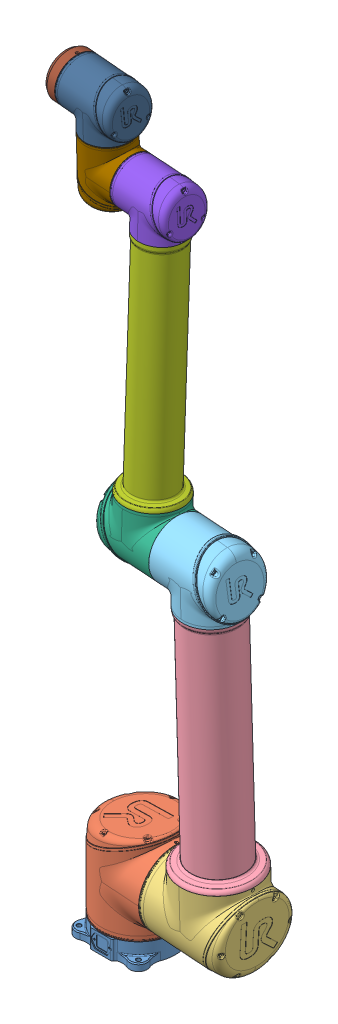
SolidWorks assembly UR10_movable, configuration Default. Lengths in mm.
Overall size (623.67 1479.02 760.18).
13 component instances, 11 part files, 13 mates.
Components (placement in the parent):
- Base-1: Base [Default] at origin size (150 38 151)
- Motor1-1: Motor1 [Default] x (-0.065799 0 0.997833) z (-0.997833 0 -0.065799) size (163.23 199.46 221.51)
- Assem3^UR10_movable-1: Assem3^UR10_movable [Default] at (0.9951 0.8966 -15.0908) x (-0.687172 -0.090957 0.720778) z (-0.726453 0.075412 -0.683066) size (271.39 766.3 275.37) (virtual)
  - Motor2-1: Motor2 [Default] at (8.9202 0.5256 -7.3957) x (0.766663 0.090526 -0.635636) z (0.638256 0 0.769824) size (162.4 221.51 199.46)
  - Link1-1: Link1 [Default] at (-262.9345 -6.1398 -216.9419) x (-0.416864 -0.081693 0.90529) z (-0.906293 -0.039003 -0.420846) size (150 460.6 150)
  - Motor3-1: Motor3 [Default] at (8.4032 1.2693 -6.9671) x (0.766663 0.090526 -0.635636) z (0.638256 0 0.769824) size (122.2 127.99 142.04)
- Assem4^UR10_movable-1: Assem4^UR10_movable [Default] at (18.2939 61.5208 -277.4221) x (-0.681689 -0.358791 0.637628) z (-0.730999 0.297471 -0.614127) size (429.3 645.83 371.98) (virtual)
  - Motor4-1: Motor4 [Default] at (239.8604 95.0312 -198.8668) x (0.668649 0.495561 -0.554373) z (0.638256 0 0.769824) size (122.2 127.38 132.89)
  - Link2-1: Link2 [Default] at (196.8587 74.4286 -194.1564) x (0.88877 0.250612 0.383773) z (-0.254068 -0.42752 0.867569) size (116 451.3 116)
  - Motor5-1: Motor5 [Default] at (178.3443 95.0312 -273.0635) x (-0.668649 -0.495561 0.554373) z (-0.638256 0 -0.769824) size (98 194.56 134.84)
- Motor6-1: Motor6 [Default] at (99.1486 0.3458 -38.7895) x (0.065764 0.03279 -0.997296) z (0.997833 0 0.065799) size (98 134.84 194.56)
- Motor7-1: Motor7 [Default] at (98.9282 0.2491 -35.8503) x (0.083707 0.032784 -0.995951) z (0.996488 -0.00059 0.083733) size (98 194.56 134.84)
- Bracket-1: Bracket [Default] at (96.299 2855.4735 15.5573) x (-0.083735 -0.003243 0.996483) z (0.996488 -0.00059 0.083733) size (90 90.13 30.68)
Mates (geometry in assembly coordinates):
- Concentric1: concentric aligned: cylinder of Base-1 through (0 0 0) axis (0 1 0) radius 75; cylinder of Motor1-1 through (0 210.0029 0) axis (0 1 0) radius 75.01
- Coincident1: coincident anti-aligned: plane of Base-1 through (-53.033 38 -53.033) normal (0 1 0); plane of Motor1-1 through (74.6379 38 4.9218) normal (0 -1 0)
- Coincident9: coincident anti-aligned: plane of Motor6-1 through (-112.0184 1373.607 -7.5637) normal (-0.002158 0.999462 0.032718); plane of Motor7-1 through (-71.0345 1372.1645 39.2036) normal (0.002158 -0.999462 -0.032718)
- Concentric9: concentric aligned: circle of Motor6-1; circle of Motor7-1
- Concentric10: concentric anti-aligned: cylinder of Motor7-1 through (-67.4679 1427.578 -2.8514) axis (-0.996488 0.00059 -0.083733) radius 45; cylinder of Bracket-1 through (-159.3441 1427.6324 -10.5716) axis (0.996488 -0.00059 0.083733) radius 45
- Coincident10: coincident anti-aligned: plane of Motor7-1 through (-129.0478 1472.3543 -6.5532) normal (-0.996488 0.00059 -0.083733); plane of Bracket-1 through (-125.1831 1427.7603 -52.8595) normal (0.996488 -0.00059 0.083733)
- Coincident20: coordinate: unknown of Base-1
- Coincident25: coincident anti-aligned: plane of Motor1-1 through (80.9445 128 79.4984) normal (0.997833 0 0.065799); plane of Assem3^UR10_movable-1/Motor2-1 through (85.6769 202.7711 7.7319) normal (-0.997833 0 -0.065799)
- Concentric19: concentric anti-aligned: circle of Motor1-1; circle of Assem3^UR10_movable-1/Motor2-1
- Concentric21: concentric anti-aligned: cylinder of Assem3^UR10_movable-1/Motor3-1 through (106.9451 740.6635 24.1132) axis (-0.997833 0 -0.065799) radius 58; cylinder of Assem4^UR10_movable-1/Motor4-1 through (237.2448 740.6635 32.7055) axis (0.997833 0 0.065799) radius 58
- Coincident27: coincident anti-aligned: plane of Assem3^UR10_movable-1/Motor3-1 through (106.5367 740.6635 24.0863) normal (-0.997833 0 -0.065799); plane of Assem4^UR10_movable-1/Motor4-1 through (106.5367 740.6635 24.0863) normal (0.997833 0 0.065799)
- Coincident28: coincident anti-aligned: plane of Assem4^UR10_movable-1/Motor5-1 through (-13.2362 1356.6788 -4.586) normal (-0.997833 0 -0.065799); plane of Motor6-1 through (-10.4417 1313.3829 -46.9648) normal (0.997833 0 0.065799)
- Concentric22: concentric aligned: circle of Assem4^UR10_movable-1/Motor5-1; circle of Motor6-1
